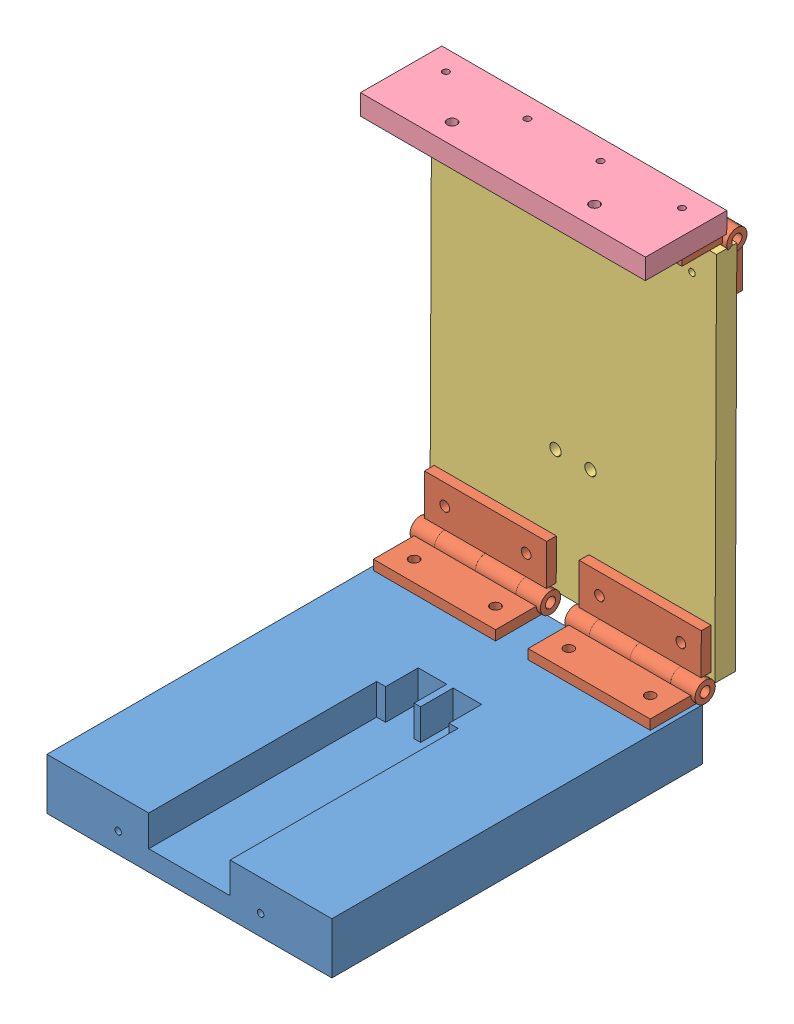
SolidWorks assembly Pack_and_go_Electroporation BoxElectroporation Box ASSEMB, configuration Default. Lengths in mm.
Overall size (88.9 145.88 129.54).
15 component instances, 4 part files, 20 mates.
Components (placement in the parent):
- Pack_and_go_Electroporation BoxElectroporation Box - single chamber-1: Pack_and_go_Electroporation BoxElectroporation Box - single chamber [Default] at (-67.9743 -16.7671 73.1549) size (88.9 16 115.57)
- Pack_and_go_Electroporation BoxHinge Full-1: Pack_and_go_Electroporation BoxHinge Full [Default] at (54.2694 -4.1456 -60.5693) size (40.64 19.08 19.12)
  - Pack_and_go_Electroporation BoxHinge-1: Pack_and_go_Electroporation BoxHinge [Default] at (-53.6638 3.3805 25.2027) size (39.37 6.35 19.05)
  - Pack_and_go_Electroporation BoxHinge-2: Pack_and_go_Electroporation BoxHinge [Default] at (-53.6638 14.353 14.1835) x (-1 0 0) z (0 0.999991 -0.004245) size (39.37 6.35 19.05)
- Pack_and_go_Electroporation BoxHinge Full-2: Pack_and_go_Electroporation BoxHinge Full [Default] at (6.0094 -4.1456 -60.5693) size (40.64 19.08 19.12)
  - Pack_and_go_Electroporation BoxHinge-1: Pack_and_go_Electroporation BoxHinge [Default] at (-53.6638 3.3805 25.2027) size (39.37 6.35 19.05)
  - Pack_and_go_Electroporation BoxHinge-2: Pack_and_go_Electroporation BoxHinge [Default] at (-53.6638 14.353 14.1835) x (-1 0 0) z (0 0.999991 -0.004245) size (39.37 6.35 19.05)
- Pack_and_go_Electroporation BoxLid-1: Pack_and_go_Electroporation BoxLid [Default] at (-23.5243 60.9434 -46.6012) x (1 0 0) z (0 0.999991 -0.004245) size (88.9 6.35 115.57)
- Pack_and_go_Electroporation BoxHinge Full 2-8: Pack_and_go_Electroporation BoxHinge Full 2 [Default] at (6.0094 136.8276 -59.702) x (1 0 0) z (0 -0.999991 0.004245) size (40.64 19.05 19.05)
  - Pack_and_go_Electroporation BoxHinge-1: Pack_and_go_Electroporation BoxHinge [Default] at (-53.6638 3.3805 25.2027) size (39.37 6.35 19.05)
  - Pack_and_go_Electroporation BoxHinge-2: Pack_and_go_Electroporation BoxHinge [Default] at (-53.6638 14.3661 14.2173) x (-1 0 0) z (0 1 0.000022) size (39.37 6.35 19.05)
- Pack_and_go_Electroporation BoxHinge Full 2-9: Pack_and_go_Electroporation BoxHinge Full 2 [Default] at (54.2694 136.8276 -59.702) x (1 0 0) z (0 -0.999991 0.004245) size (40.64 19.05 19.05)
  - Pack_and_go_Electroporation BoxHinge-1: Pack_and_go_Electroporation BoxHinge [Default] at (-53.6638 3.3805 25.2027) size (39.37 6.35 19.05)
  - Pack_and_go_Electroporation BoxHinge-2: Pack_and_go_Electroporation BoxHinge [Default] at (-53.6638 14.3661 14.2173) x (-1 0 0) z (0 1 0.000022) size (39.37 6.35 19.05)
- Pack_and_go_Electroporation BoxElectroporation Box - door-4: Pack_and_go_Electroporation BoxElectroporation Box - door [Default] at (-67.9743 129.0013 -50.0649) x (1 0 0) z (0 -0.999991 0.004223) size (88.9 25.4 6.35)
Mates (geometry in assembly coordinates):
- Coincident1: coincident anti-aligned: plane of Pack_and_go_Electroporation BoxElectroporation Box - single chamber-1 through (-67.9743 -0.7651 73.1549) normal (0 1 0); plane of Pack_and_go_Electroporation BoxHinge Full-1/Pack_and_go_Electroporation BoxHinge-1 through (0.6057 -0.7651 -35.3666) normal (0 -1 0)
- Coincident3: coincident anti-aligned: line of Pack_and_go_Electroporation BoxElectroporation Box - single chamber-1 through (-67.9743 -0.7651 -42.4151) axis (1 0 0); line of Pack_and_go_Electroporation BoxHinge Full-1/Pack_and_go_Electroporation BoxHinge-1 through (19.6557 -0.7651 -42.4151) axis (-1 0 0)
- Coincident7: coincident: plane of Pack_and_go_Electroporation BoxElectroporation Box - single chamber-1 through (-67.9743 -0.7651 -42.4151) normal (0 0 -1); line of Pack_and_go_Electroporation BoxHinge Full-2/Pack_and_go_Electroporation BoxHinge-1 through (-47.6543 -0.7651 -42.4151) axis (-1 0 0)
- Coincident8: coincident anti-aligned: plane of Pack_and_go_Electroporation BoxElectroporation Box - single chamber-1 through (-67.9743 -0.7651 73.1549) normal (0 1 0); plane of Pack_and_go_Electroporation BoxHinge Full-2/Pack_and_go_Electroporation BoxHinge-1 through (-47.6543 -0.7651 -35.3666) normal (0 -1 0)
- Concentric3: concentric aligned: circle of Pack_and_go_Electroporation BoxElectroporation Box - single chamber-1; circle of Pack_and_go_Electroporation BoxHinge Full-2/Pack_and_go_Electroporation BoxHinge-1
- Concentric4: concentric aligned: circle of Pack_and_go_Electroporation BoxElectroporation Box - single chamber-1; circle of Pack_and_go_Electroporation BoxHinge Full-1/Pack_and_go_Electroporation BoxHinge-1
- Coincident10: coincident anti-aligned: plane of Pack_and_go_Electroporation BoxHinge Full-2/Pack_and_go_Electroporation BoxHinge-2 through (-47.6543 10.2074 -46.3858) normal (0 -0.004245 -0.999991); plane of Pack_and_go_Electroporation BoxLid-1 through (-23.5243 60.9434 -46.6012) normal (0 0.004245 0.999991)
- Concentric6: concentric aligned: circle of Pack_and_go_Electroporation BoxHinge Full-2/Pack_and_go_Electroporation BoxHinge-2; circle of Pack_and_go_Electroporation BoxLid-1
- Concentric7: concentric aligned: circle of Pack_and_go_Electroporation BoxHinge Full-1/Pack_and_go_Electroporation BoxHinge-2; circle of Pack_and_go_Electroporation BoxLid-1
- Concentric16: concentric anti-aligned: circle of Pack_and_go_Electroporation BoxLid-1; circle of Pack_and_go_Electroporation BoxHinge Full 2-9/Pack_and_go_Electroporation BoxHinge-1
- Concentric18: concentric anti-aligned: circle of Pack_and_go_Electroporation BoxLid-1; circle of Pack_and_go_Electroporation BoxHinge Full 2-9/Pack_and_go_Electroporation BoxHinge-1
- Concentric19: concentric anti-aligned: circle of Pack_and_go_Electroporation BoxLid-1; circle of Pack_and_go_Electroporation BoxHinge Full 2-8/Pack_and_go_Electroporation BoxHinge-1
- Concentric20: concentric anti-aligned: circle of Pack_and_go_Electroporation BoxLid-1; circle of Pack_and_go_Electroporation BoxHinge Full 2-8/Pack_and_go_Electroporation BoxHinge-1
- Coincident26: coincident anti-aligned: plane of Pack_and_go_Electroporation BoxLid-1 through (-23.5243 60.9165 -52.9511) normal (0 -0.004245 -0.999991); plane of Pack_and_go_Electroporation BoxHinge Full 2-9/Pack_and_go_Electroporation BoxHinge-1 through (0.6057 111.6525 -53.1665) normal (0 0.004245 0.999991)
- Coincident27: coincident anti-aligned: plane of Pack_and_go_Electroporation BoxLid-1 through (-23.5243 60.9165 -52.9511) normal (0 -0.004245 -0.999991); plane of Pack_and_go_Electroporation BoxHinge Full 2-8/Pack_and_go_Electroporation BoxHinge-1 through (-47.6543 111.6525 -53.1665) normal (0 0.004245 0.999991)
- Concentric21: concentric anti-aligned: circle of Pack_and_go_Electroporation BoxHinge Full 2-8/Pack_and_go_Electroporation BoxHinge-2; circle of Pack_and_go_Electroporation BoxElectroporation Box - door-4
- Concentric22: concentric anti-aligned: circle of Pack_and_go_Electroporation BoxHinge Full 2-8/Pack_and_go_Electroporation BoxHinge-2; circle of Pack_and_go_Electroporation BoxElectroporation Box - door-4
- Concentric23: concentric anti-aligned: circle of Pack_and_go_Electroporation BoxHinge Full 2-9/Pack_and_go_Electroporation BoxHinge-2; circle of Pack_and_go_Electroporation BoxElectroporation Box - door-4
- Concentric24: concentric anti-aligned: circle of Pack_and_go_Electroporation BoxHinge Full 2-9/Pack_and_go_Electroporation BoxHinge-2; circle of Pack_and_go_Electroporation BoxElectroporation Box - door-4
- Coincident28: coincident anti-aligned: plane of Pack_and_go_Electroporation BoxHinge Full 2-9/Pack_and_go_Electroporation BoxHinge-2 through (0.6057 122.6714 -45.2757) normal (0 0.999991 -0.004223); plane of Pack_and_go_Electroporation BoxElectroporation Box - door-4 through (-67.9743 122.6513 -50.0381) normal (0 -0.999991 0.004223)
